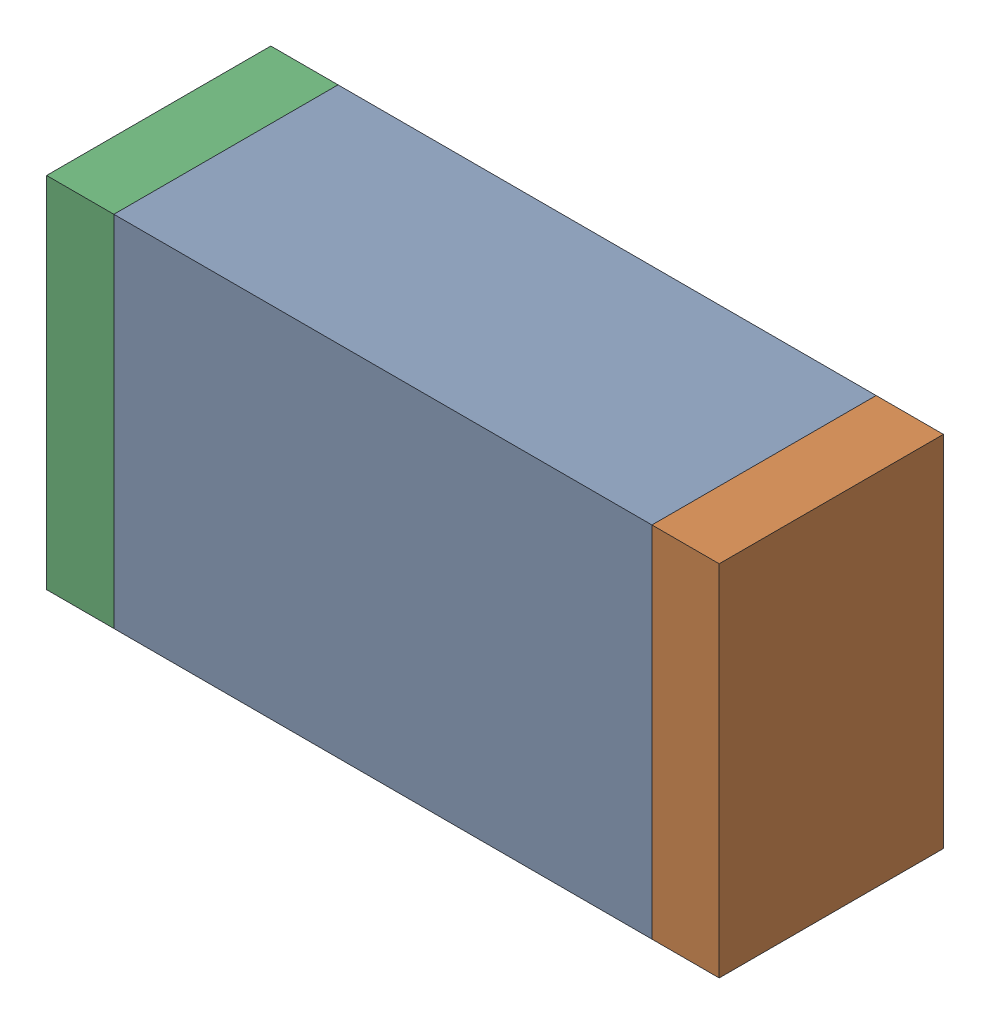
SolidWorks assembly R56, configuration Default. Lengths in mm.
Overall size (1.5 0.8 0.5).
6 component instances, 2 part files, 0 mates.
Components (placement in the parent):
- 836752368-1: 836752368 [Default] at (119.05 65.2 0) size (1.2 0.8 0.5)
  - Extruded-1: Extruded [Default] at origin size (1.2 0.8 0.5)
- 836752496-1: 836752496 [Default] at (119.725 65.2 0) size (0.15 0.8 0.5)
  - Extruded_2-1: Extruded_2 [Default] at origin size (0.15 0.8 0.5)
- 836752496-2: 836752496 [Default] at (118.375 65.2 0) size (0.15 0.8 0.5)
  - Extruded_2-1: Extruded_2 [Default] at origin size (0.15 0.8 0.5)
